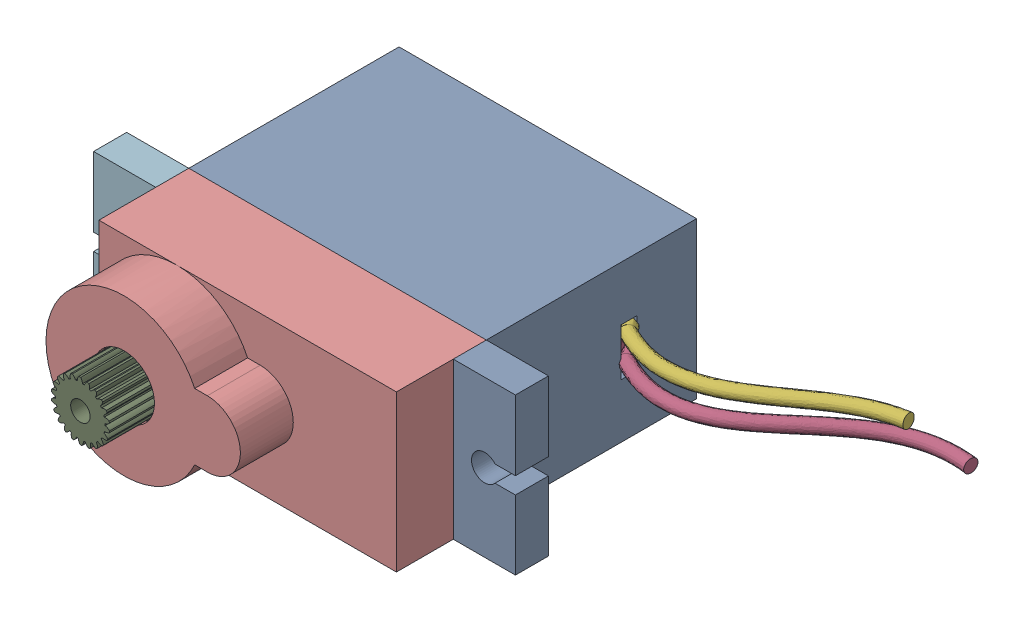
SolidWorks assembly SERVO_MOTEUR, configuration Default. Lengths in mm.
Overall size (45.89 13.05 32.84).
10 component instances, 10 part files, 0 mates.
Components (placement in the parent):
- lower cover-1: lower cover [Varsayılan] at (-10.9275 3.0017 -4.223) size (22.5 11.8 15.9)
- motor-1: motor [Varsayılan] at (-9.5275 2.9783 11.077) x (-0.99999 -0.004374 0) z (0 0 -1) size (7.83 7.83 13.56)
- feedback potentiometer-1: feedback potentiometer [Varsayılan] at (-9.0275 3.0017 11.177) x (-1 0 0) z (0 0 -1) size (7.71 7.36 13.7)
- Part6^servo motor assembley-1: Part6^servo motor assembley [Varsayılan] at (-10.9275 3.0017 11.177) x (-1 0 0) z (0 0 -1) size (1.5 1.5 10)
- Part7^servo motor assembley-1: Part7^servo motor assembley [Varsayılan] at (-9.517 2.6091 11.927) x (0.924877 -0.380266 0) z (0 0 1) size (10 10 5.7)
- Part8^servo motor assembley-1: Part8^servo motor assembley [Varsayılan] at (-9.3501 4.3681 11.477) x (0.966834 -0.255406 0) z (0 0 1) size (3.22 3.24 1.95)
- Part10^servo motor assembley-1: Part10^servo motor assembley [Varsayılan] at (-11.9047 8.7845 13.077) x (0.603146 0.797631 0) z (0 0 1) size (8.02 8.02 12.7)
- upper cover-1: upper cover [Varsayılan] at (-10.9275 3.0017 11.677) x (-1 0 0) z (0 0 1) size (31.9 11.8 10.8)
- Part16^servo motor assembley-1: Part16^servo motor assembley [Varsayılan] at (-10.9275 3.0017 -3.723) size (11.69 9.5 1.25)
- Part21^servo motor assembley-1: Part21^servo motor assembley [Varsayılan] at (-10.9275 -2.8983 -4.223) x (-1 0 0) z (0 -1 0) size (34.03 15.81 10.46)
